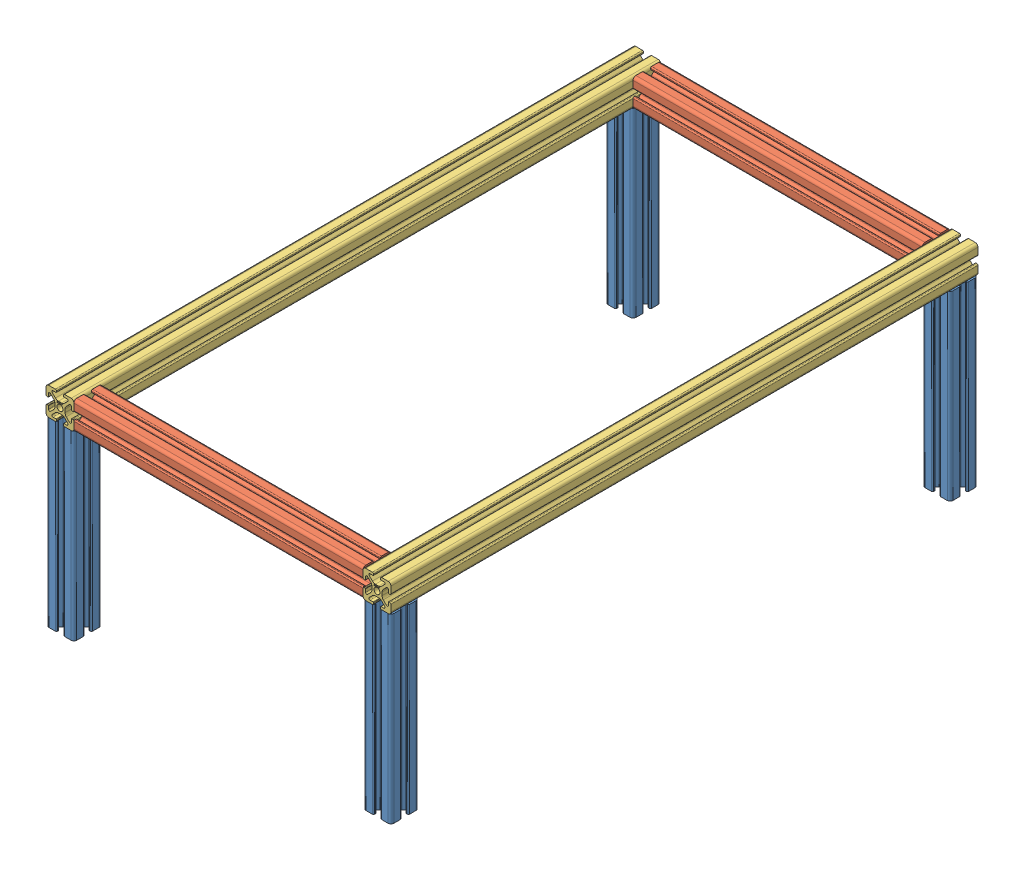
SolidWorks assembly UOM20-4A007, configuration Default. Lengths in mm.
Overall size (246.8 150.09 420.1).
10 component instances, 4 part files, 26 mates.
Components (placement in the parent):
- Vertical Beam-1: Vertical Beam [Default] at (-12.7433 375.5327 464.8294) x (0 0 -1) z (0 -1 0) size (19.99 19.99 130.1)
- Vertical Beam-2: Vertical Beam [Default] at (-12.7433 375.5327 64.8192) x (1 0 0) z (0 -1 0) size (19.99 19.99 130.1)
- Vertical Beam-3: Vertical Beam [Default] at (214.0665 375.5327 64.8192) x (1 0 0) z (0 -1 0) size (19.99 19.99 130.1)
- Vertical Beam-4: Vertical Beam [Default] at (214.0665 375.5327 464.8294) x (0 0 1) z (0 -1 0) size (19.99 19.99 130.1)
- Top  parallel horontal Beam 250mm-1: Top  parallel horontal Beam 250mm [Default] at (-2.7484 385.5276 464.8294) x (0 -1 0) z (1 0 0) size (19.99 19.99 206.92)
- Top  parallel horontal Beam 250mm-2: Top  parallel horontal Beam 250mm [Default] at (204.0716 385.5276 64.8192) x (0 0 1) z (-1 0 0) size (19.99 19.99 206.92)
- Top horontal Beam-1: Top horontal Beam [Default] at (214.0665 385.5276 54.8243) size (19.99 19.99 420.1)
- Top horontal Beam-2: Top horontal Beam [Default] at (-12.7433 385.5276 54.8243) size (19.99 19.99 420.1)
- 5537T935_ALUMINUM T-SLOTTED FRAMING EXTRUSION (20mm)-1: 5537T935_ALUMINUM T-SLOTTED FRAMING EXTRUSION (20mm) [5537T935] at (204.0716 385.5276 74.8141) x (-1 0 0) z (0 1 0) (suppressed, hidden)
- 5537T935_ALUMINUM T-SLOTTED FRAMING EXTRUSION (20mm)-2: 5537T935_ALUMINUM T-SLOTTED FRAMING EXTRUSION (20mm) [5537T935] at (204.0716 375.5327 64.8192) x (0 -1 0) z (0 0 -1) (suppressed, hidden)
Mates (geometry in assembly coordinates):
- Parallel4: parallel aligned: plane of Vertical Beam-4 through (224.0614 245.5327 472.8177) normal (1 0 0); plane of Top horontal Beam-1 through (224.0614 377.5393 474.8243) normal (1 0 0)
- Parallel5: parallel aligned: plane of Vertical Beam-4 through (222.0548 245.5327 474.8243) normal (0 0 1); plane of Top horontal Beam-1 through (212.9331 392.1527 474.8243) normal (0 0 1)
- Coincident19: coincident: point of Vertical Beam-4; point of Top horontal Beam-1
- Coincident20: coincident anti-aligned: plane of Top  parallel horontal Beam 250mm-1 through (204.0716 386.661 458.2043) normal (1 0 0); plane of Top horontal Beam-1 through (204.0716 393.5159 474.8243) normal (-1 0 0)
- Coincident21: coincident: point of Top  parallel horontal Beam 250mm-1; point of Top horontal Beam-1
- Parallel6: parallel aligned: plane of Top  parallel horontal Beam 250mm-1 through (204.0716 395.5225 472.8177) normal (0 1 0); plane of Top horontal Beam-1 through (206.0782 395.5225 474.8243) normal (0 1 0)
- Coincident26: coincident anti-aligned: plane of Top  parallel horontal Beam 250mm-2 through (204.0716 392.1527 63.6858) normal (1 0 0); plane of Top horontal Beam-1 through (204.0716 393.5159 474.8243) normal (-1 0 0)
- Coincident27: coincident aligned: plane of Top  parallel horontal Beam 250mm-2 through (-2.7484 393.5159 54.8243) normal (0 0 -1); plane of Top horontal Beam-1 through (212.9331 392.1527 54.8243) normal (0 0 -1)
- Coincident28: coincident: point of Top  parallel horontal Beam 250mm-2; point of Top horontal Beam-1
- Parallel9: parallel aligned: plane of Vertical Beam-2 through (-20.7316 245.5327 54.8243) normal (0 0 -1); plane of Top horontal Beam-2 through (-13.8767 392.1527 54.8243) normal (0 0 -1)
- Coincident30: coincident aligned: plane of Vertical Beam-2 through (-22.7382 245.5327 56.8309) normal (-1 0 0); plane of Top horontal Beam-2 through (-22.7382 393.5159 474.8243) normal (-1 0 0)
- Coincident31: coincident: point of Vertical Beam-2; point of Top horontal Beam-2
- Coincident32: coincident anti-aligned: plane of Top  parallel horontal Beam 250mm-2 through (-2.7484 392.1527 63.6858) normal (-1 0 0); plane of Top horontal Beam-2 through (-2.7484 393.5159 474.8243) normal (1 0 0)
- Coincident33: coincident aligned: plane of Top  parallel horontal Beam 250mm-2 through (-2.7484 393.5159 54.8243) normal (0 0 -1); plane of Top horontal Beam-2 through (-13.8767 392.1527 54.8243) normal (0 0 -1)
- Coincident34: coincident: point of Top  parallel horontal Beam 250mm-2; point of Top horontal Beam-2
- Parallel10: parallel anti-aligned: plane of Top horontal Beam-1 through (204.0716 393.5159 474.8243) normal (-1 0 0); plane of 5537T935_ALUMINUM T-SLOTTED FRAMING EXTRUSION (20mm)-1 through (204.0716 394.5276 74.8141) normal (1 0 0)
- Coincident37: coincident anti-aligned: plane of Top  parallel horontal Beam 250mm-2 through (-2.7484 393.5159 74.8141) normal (0 0 1); plane of 5537T935_ALUMINUM T-SLOTTED FRAMING EXTRUSION (20mm)-1 through (184.0716 394.5276 74.8141) normal (0 0 -1)
- Coincident38: coincident anti-aligned: line of Top  parallel horontal Beam 250mm-2 through (204.0716 388.8169 74.8141) axis (0 1 0); line of 5537T935_ALUMINUM T-SLOTTED FRAMING EXTRUSION (20mm)-1 through (204.0716 394.5276 74.8141) axis (0 -1 0)
- Width1: width anti-aligned: plane of 5537T935_ALUMINUM T-SLOTTED FRAMING EXTRUSION (20mm)-1 through (204.0716 394.5276 91.8141) normal (0 1 0); plane of 5537T935_ALUMINUM T-SLOTTED FRAMING EXTRUSION (20mm)-1 through (204.0716 376.5276 91.8141) normal (0 -1 0); plane of Top horontal Beam-1 through (206.0782 375.5327 474.8243) normal (0 -1 0); plane of Top horontal Beam-1 through (206.0782 395.5225 474.8243) normal (0 1 0)
- Width2: width anti-aligned: plane of 5537T935_ALUMINUM T-SLOTTED FRAMING EXTRUSION (20mm)-2 through (187.0716 375.5327 55.8192) normal (0 0 -1); plane of 5537T935_ALUMINUM T-SLOTTED FRAMING EXTRUSION (20mm)-2 through (187.0716 375.5327 73.8192) normal (0 0 1); plane of Vertical Beam-3 through (206.0782 245.5327 74.8141) normal (0 0 1); plane of Vertical Beam-3 through (206.0782 245.5327 54.8243) normal (0 0 -1)
- Coincident39: coincident anti-aligned: line of Vertical Beam-3 through (204.0716 375.5327 61.5299) axis (0 0 -1); line of 5537T935_ALUMINUM T-SLOTTED FRAMING EXTRUSION (20mm)-2 through (204.0716 375.5327 55.8192) axis (0 0 1)
- Coincident40: coincident anti-aligned: plane of Top  parallel horontal Beam 250mm-2 through (-2.7484 375.5327 56.8309) normal (0 -1 0); plane of 5537T935_ALUMINUM T-SLOTTED FRAMING EXTRUSION (20mm)-2 through (204.0716 375.5327 55.8192) normal (0 1 0)
- Coincident41: coincident aligned: plane of Vertical Beam-1 through (-20.7316 245.5327 474.8243) normal (0 0 1); plane of Top horontal Beam-2 through (-13.8767 392.1527 474.8243) normal (0 0 1)
- Coincident42: coincident: moEndPointRef_w of Vertical Beam-1; plane of Top horontal Beam-2 through (-20.7316 375.5327 474.8243) normal (0 -1 0)
- Coincident43: coincident aligned: plane of Vertical Beam-1 through (-22.7382 245.5327 472.8177) normal (-1 0 0); plane of Top horontal Beam-2 through (-22.7382 377.5393 474.8243) normal (-1 0 0)
- Coincident44: coincident aligned: plane of Vertical Beam-3 through (206.0782 245.5327 54.8243) normal (0 0 -1); plane of Top horontal Beam-1 through (212.9331 392.1527 54.8243) normal (0 0 -1)
